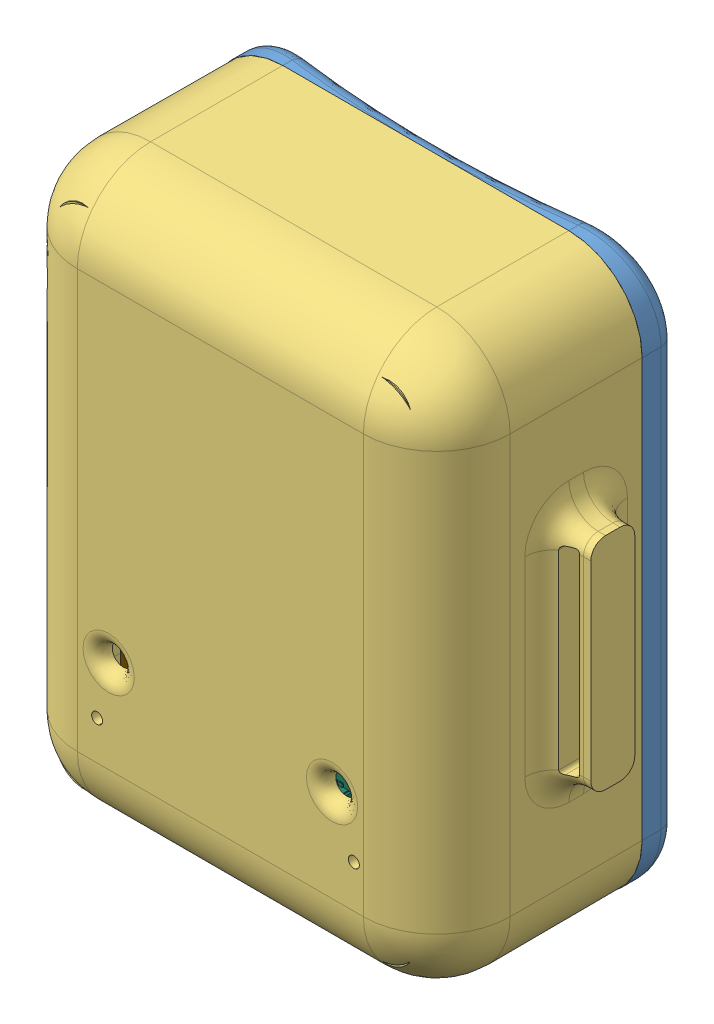
SolidWorks assembly Episafe-assembly-v2, configuration Default. Lengths in mm.
Overall size (69 77 32.99).
69 component instances, 18 part files, 10 mates.
Components (placement in the parent):
- Episafev1v2(p1)-1: Episafev1v2(p1) [Default] at (18.2209 42.0383 58.3925) size (59 77 20.49)
- bt-1: bt [Default] at (18.2209 34.0383 63.8925) size (34 50 13)
- Episafev2(p2)-1: Episafev2(p2) [Default] at (18.2209 42.0383 63.3925) size (69 77 28)
- Episafe.step-2: Episafe.step [Default] at (108.7209 149.5383 78.8925) x (0 -1 0) z (0 0 1) size (67 53.88 12.81)
  - C_1206_3216Metric.step-1: C_1206_3216Metric.step [Default] at (87.35 -103.2 1.65) x (-1 0 0) z (0 0 1) size (3.2 1.6 1.6)
    - SOLID.step-1: SOLID.step [Default] at origin size (3.2 1.6 1.6)
  - R_1206_3216Metric.step-1: R_1206_3216Metric.step [Default] at (118 -73.55 1.65) x (-1 0 0) z (0 0 1) size (3.2 1.6 0.55)
    - SOLID-0.step-1: SOLID-0.step [Default] at origin size (3.2 1.6 0.55)
  - R_1206_3216Metric.step-2: R_1206_3216Metric.step [Default] at (123.5 -100.2 1.65) x (-1 0 0) z (0 0 1) size (3.2 1.6 0.55)
    - SOLID-0.step-1: SOLID-0.step [Default] at origin size (3.2 1.6 0.55)
  - C_1206_3216Metric.step-2: C_1206_3216Metric.step [Default] at (81.875 -103.225 1.65) x (-1 0 0) z (0 0 1) size (3.2 1.6 1.6)
    - SOLID.step-1: SOLID.step [Default] at origin size (3.2 1.6 1.6)
  - R_1206_3216Metric.step-3: R_1206_3216Metric.step [Default] at (87.2625 -99.675 1.65) x (-1 0 0) z (0 0 1) size (3.2 1.6 0.55)
    - SOLID-0.step-1: SOLID-0.step [Default] at origin size (3.2 1.6 0.55)
  - TO-92_Inline.step-1: TO-92_Inline.step [Default] at (115.89 -100.105 1.65) x (0 -1 0) z (0 0 1) size (4.83 3.75 9.8)
    - SOLID-1.step-1: SOLID-1.step [Default] at origin size (4.83 3.75 9.8)
  - TO-92_Inline.step-2: TO-92_Inline.step [Default] at (110.69 -100.105 1.65) x (0 -1 0) z (0 0 1) size (4.83 3.75 9.8)
    - SOLID-1.step-1: SOLID-1.step [Default] at origin size (4.83 3.75 9.8)
  - R_1206_3216Metric.step-4: R_1206_3216Metric.step [Default] at (111.8 -73.6 1.65) size (3.2 1.6 0.55)
    - SOLID-0.step-1: SOLID-0.step [Default] at origin size (3.2 1.6 0.55)
  - MPU_6050.step-1: MPU_6050.step [Default] at (92.283 -75.47 7.65) x (-1 0 0) z (0 0 1) size (20.5 16 3)
    - COMPOUND.step-1: COMPOUND.step [Default] at origin size (20.5 16 3)
  - R_1206_3216Metric.step-5: R_1206_3216Metric.step [Default] at (108.575 -80.65 1.65) x (0 1 0) z (0 0 1) size (3.2 1.6 0.55)
    - SOLID-0.step-1: SOLID-0.step [Default] at origin size (3.2 1.6 0.55)
  - R_1206_3216Metric.step-6: R_1206_3216Metric.step [Default] at (117.845 -107.305 1.65) size (3.2 1.6 0.55)
    - SOLID-0.step-1: SOLID-0.step [Default] at origin size (3.2 1.6 0.55)
  - R_1206_3216Metric.step-7: R_1206_3216Metric.step [Default] at (112.9 -76.5 1.65) x (-1 0 0) z (0 0 1) size (3.2 1.6 0.55)
    - SOLID-0.step-1: SOLID-0.step [Default] at origin size (3.2 1.6 0.55)
  - LED_D3.0mm.step-1: LED_D3.0mm.step [Default] at (123.4 -74 1.65) x (0 -1 0) z (0 0 1) size (3.41 3.8 10.8)
    - SOLID-2.step-1: SOLID-2.step [Default] at origin size (3.41 3.8 10.8)
  - R_1206_3216Metric.step-8: R_1206_3216Metric.step [Default] at (106.8 -101.5 1.65) x (0 -1 0) z (0 0 1) size (3.2 1.6 0.55)
    - SOLID-0.step-1: SOLID-0.step [Default] at origin size (3.2 1.6 0.55)
  - R_1206_3216Metric.step-9: R_1206_3216Metric.step [Default] at (121.9 -111.3 1.65) x (0 -1 0) z (0 0 1) size (3.2 1.6 0.55)
    - SOLID-0.step-1: SOLID-0.step [Default] at origin size (3.2 1.6 0.55)
  - PinSocket_1x07_P2.54mm_Vertical.step-1: PinSocket_1x07_P2.54mm_Vertical.step [Default] at (106.82 -68.7 1.65) x (0 1 0) z (0 0 1) size (2.54 17.78 10.1)
    - SOLID-3.step-1: SOLID-3.step [Default] at origin size (2.54 17.78 10.1)
  - C_1206_3216Metric.step-3: C_1206_3216Metric.step [Default] at (115.775 -111.35 1.65) x (0 -1 0) z (0 0 1) size (3.2 1.6 1.6)
    - SOLID.step-1: SOLID.step [Default] at origin size (3.2 1.6 1.6)
  - C_1206_3216Metric.step-4: C_1206_3216Metric.step [Default] at (81.875 -99.65 1.65) x (-1 0 0) z (0 0 1) size (3.2 1.6 1.6)
    - SOLID.step-1: SOLID.step [Default] at origin size (3.2 1.6 1.6)
  - SW_PUSH_6mm_H7.3mm.step-1: SW_PUSH_6mm_H7.3mm.step [Default] at (132.95 -104.15 1.65) x (0 -1 0) z (0 0 1) size (7.17 6 10.8)
    - SOLID-4.step-1: SOLID-4.step [Default] at origin size (7.17 6 10.8)
  - PinSocket_1x04_P2.54mm_Vertical.step-1: PinSocket_1x04_P2.54mm_Vertical.step [Default] at (94.12 -99 1.65) x (0 1 0) z (0 0 1) size (2.54 10.16 10.1)
    - SOLID-5.step-1: SOLID-5.step [Default] at origin size (2.54 10.16 10.1)
  - SW_Tactile_SPST_Angled_PTS645Vx83-2LFS.step-1: SW_Tactile_SPST_Angled_PTS645Vx83-2LFS.step [Default] at (86.85 -110.815 1.65) x (-1 0 0) z (0 0 1) size (7.4 12.4 11)
    - SOLID-6.step-1: SOLID-6.step [Default] at origin size (7.4 12.4 11)
  - C_1206_3216Metric.step-5: C_1206_3216Metric.step [Default] at (108.295 -111.455 1.65) x (0 -1 0) z (0 0 1) size (3.2 1.6 1.6)
    - SOLID.step-1: SOLID.step [Default] at origin size (3.2 1.6 1.6)
  - SW_PUSH_6mm_H7.3mm.step-2: SW_PUSH_6mm_H7.3mm.step [Default] at (132.45 -69.15 1.65) x (0 -1 0) z (0 0 1) size (7.17 6 10.8)
    - SOLID-4.step-1: SOLID-4.step [Default] at origin size (7.17 6 10.8)
  - SOT-23-5.step-1: SOT-23-5.step [Default] at (112.195 -111.205 1.65) x (0 1 0) z (0 0 1) size (2.8 2.9 1.55)
    - SOLID-7.step-1: SOLID-7.step [Default] at origin size (2.8 2.9 1.55)
  - C_1206_3216Metric.step-6: C_1206_3216Metric.step [Default] at (111.845 -107.205 1.65) size (3.2 1.6 1.6)
    - SOLID.step-1: SOLID.step [Default] at origin size (3.2 1.6 1.6)
  - R_1206_3216Metric.step-10: R_1206_3216Metric.step [Default] at (125 -111.25 1.65) x (0 1 0) z (0 0 1) size (3.2 1.6 0.55)
    - SOLID-0.step-1: SOLID-0.step [Default] at origin size (3.2 1.6 0.55)
  - KiCAD-ESP-WROOM-32.step-1: KiCAD-ESP-WROOM-32.step [Default] at (92.46 -86.2 1.65) x (0 -1 0) z (0 0 1) size (18.07 25.54 3.04)
    - COMPOUND-8.step-1: COMPOUND-8.step [Default] at origin size (18.07 25.54 3.04)
  - R_1206_3216Metric.step-11: R_1206_3216Metric.step [Default] at (119 -111.325 1.65) x (0 -1 0) z (0 0 1) size (3.2 1.6 0.55)
    - SOLID-0.step-1: SOLID-0.step [Default] at origin size (3.2 1.6 0.55)
  - LED_D3.0mm.step-2: LED_D3.0mm.step [Default] at (123.4 -104.46 1.65) x (0 -1 0) z (0 0 1) size (3.41 3.8 10.8)
    - SOLID-2.step-1: SOLID-2.step [Default] at origin size (3.41 3.8 10.8)
  - TP4056 charge module with protection.step-1: TP4056 charge module with protection.step [Default] at (138.05 -79.09 2.65) size (29.27 17.02 4.6)
    - COMPOUND-9.step-1: COMPOUND-9.step [Default] at origin size (29.27 17.02 4.6)
  - Pulse.step-1: Pulse.step [Default] at (99.0506 -88.25 0.95) x (0 -1 0) z (1 0 0) size (15.88 3.81 15.88)
    - COMPOUND-10.step-1: COMPOUND-10.step [Default] at origin size (15.88 3.81 15.88)
  - C0720B001F.step-1: C0720B001F.step [Default] at (105.43 -68.7 -0.05) x (0 1 0) z (-1 0 0) size (11 2.1 7)
    - COMPOUND-11.step-1: COMPOUND-11.step [Default] at origin size (11 2.1 7)
  - Episafe PCB.step-1: Episafe PCB.step [Default] at origin size (67 49 1.6)
Mates (geometry in assembly coordinates):
- Distance1: distance = 1 mm anti-aligned: plane of bt-1 through (35.2209 9.0383 76.8925) normal (0 -1 0); plane of Episafev1v2(p1)-1 through (43.7209 8.0383 63.8925) normal (0 1 0)
- Width1: width anti-aligned: plane of Episafev1v2(p1)-1 through (-7.2791 8.0383 63.8925) normal (1 0 0); plane of Episafev1v2(p1)-1 through (43.7209 8.0383 63.8925) normal (-1 0 0); plane of bt-1 through (1.2209 9.0383 76.8925) normal (-1 0 0); plane of bt-1 through (35.2209 9.0383 76.8925) normal (1 0 0)
- Coincident2: coincident anti-aligned: plane of Episafev1v2(p1)-1 through (18.2209 42.0383 63.8925) normal (0 0 1); plane of bt-1 through (18.2209 34.0383 63.8925) normal (0 0 -1)
- InPlace1: in place: plane of Episafev1v2(p1)-1 through (-1.2791 13.5383 63.3925) normal (0 0 1); plane of ? through (0 0 63.3925) normal (0 0 1); moOrthogonalPlaneRef_w of Episafev1v2(p1)-1 through (-1.2791 13.5383 63.3925) normal (0 0 1); plane of ? through (0 0 63.3925) normal (0 1 0); plane of Episafev1v2(p1)-1 through (-1.2791 13.5383 63.3925) normal (0 0 1); plane of ? through (0 0 63.3925) normal (1 0 0); plane of Episafev1v2(p1)-1 through (-1.2791 13.5383 63.3925) normal (0 0 1); unknown of Episafev2(p2)-1
- Coincident4: coincident aligned: plane of ?; plane of ?
- Coincident5: coincident aligned: moOrthogonalPlaneRef_w of Episafev1v2(p1)-1 through (18.2209 42.0383 63.3925) normal (0 1 0); plane of Episafev2(p2)-1 through (18.2209 42.0383 63.3925) normal (0 1 0)
- Coincident6: coincident anti-aligned: moOrthogonalPlaneRef_w of Episafev1v2(p1)-1 through (18.2209 42.0383 63.3925) normal (-1 0 0); plane of Episafev2(p2)-1 through (18.2209 42.0383 63.3925) normal (1 0 0)
- Width2: width aligned: plane of Episafe.step-2/Episafe PCB.step-1 through (-6.2791 8.5383 78.8925) normal (-1 0 0); plane of Episafev1v2(p1)-1 through (42.7209 75.5383 78.8925) normal (1 0 0); plane of Episafe.step-2/Episafe PCB.step-1 through (43.7209 8.0383 63.8925) normal (-1 0 0); plane of Episafev1v2(p1)-1 through (-7.2791 8.0383 63.8925) normal (1 0 0)
- Width3: width anti-aligned: plane of Episafe.step-2/Episafe PCB.step-1 through (-6.2791 75.5383 78.8925) normal (0 1 0); plane of Episafev1v2(p1)-1 through (42.7209 8.5383 78.8925) normal (0 -1 0); plane of Episafe.step-2/Episafe PCB.step-1 through (43.7209 76.0383 63.8925) normal (0 -1 0); plane of Episafev1v2(p1)-1 through (43.7209 8.0383 63.8925) normal (0 1 0)
- Distance2: distance = 2 mm anti-aligned: plane of Episafe.step-2/Episafe PCB.step-1 through (18.2209 42.0383 78.8925) normal (0 0 -1); plane of bt-1 through (18.2209 34.0383 76.8925) normal (0 0 1)
